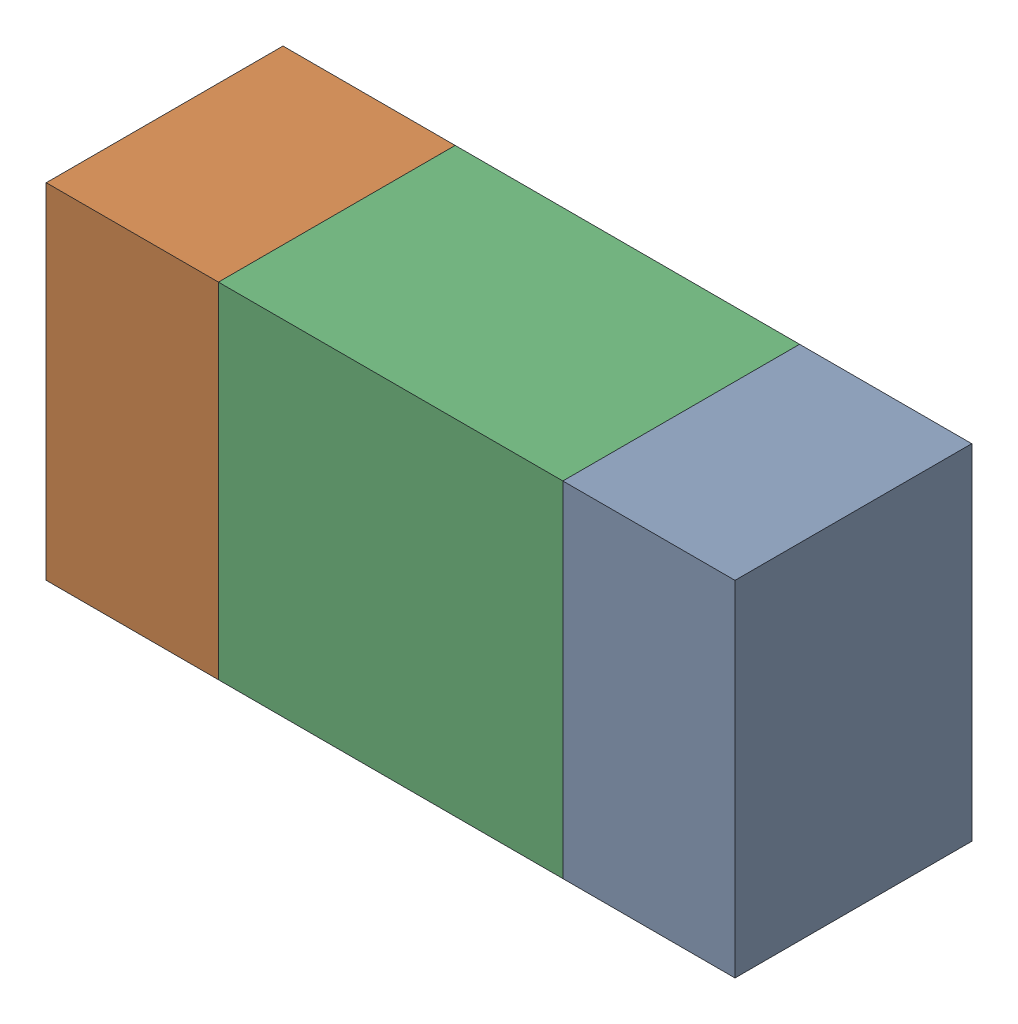
SolidWorks assembly R25, configuration ﾃﾞﾌｫﾙﾄ. Lengths in mm.
Overall size (1.6 0.8 0.55).
6 component instances, 2 part files, 0 mates.
Components (placement in the parent):
- 689261512-1: 689261512 [ﾃﾞﾌｫﾙﾄ] at (11.3949 20.9551 -1.7503) size (0.4 0.8 0.55)
  - Extruded_32-1: Extruded_32 [ﾃﾞﾌｫﾙﾄ] at origin size (0.4 0.8 0.55)
- 689261512-2: 689261512 [ﾃﾞﾌｫﾙﾄ] at (10.1949 20.9551 -1.7503) size (0.4 0.8 0.55)
  - Extruded_32-1: Extruded_32 [ﾃﾞﾌｫﾙﾄ] at origin size (0.4 0.8 0.55)
- 689261648-1: 689261648 [ﾃﾞﾌｫﾙﾄ] at (10.795 20.9551 -1.7503) size (0.8 0.8 0.55)
  - Extruded_33-1: Extruded_33 [ﾃﾞﾌｫﾙﾄ] at origin size (0.8 0.8 0.55)
